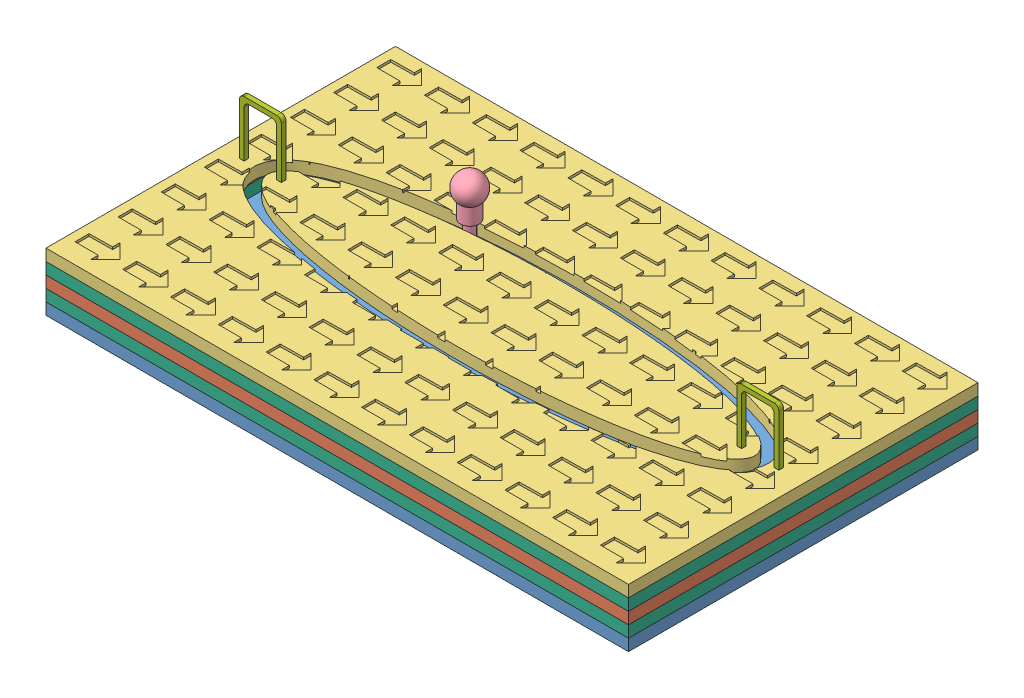
SolidWorks assembly Closedloopintegral, configuration Default. Lengths in mm.
Overall size (250 49 150).
9 component instances, 7 part files, 15 mates.
Components (placement in the parent):
- base1-1: base1 [Default] at (-49.7046 107.1468 237.7868) size (250 5 150)
- base2-2: base2 [Default] at (-49.7046 117.1468 237.7868) size (250 5 150)
- base3-1: base3 [Default] at (-49.7046 127.1468 237.7868) size (250 5 150)
- slider-1: slider [Default] at (32.305 122.1468 137.9363) x (0.152065 0 0.98837) z (-0.98837 0 0.152065) size (12.13 29.63 12.13)
- washer clip-1: washer clip [Default] at (32.305 122.1468 137.9363) x (-1 0 0) z (0 0 -1) size (11.02 5 8)
- base2_1-1: base2_1 [Default] at (-49.7046 112.1468 237.7868) size (250 5 150)
- base2_1-2: base2_1 [Default] at (-49.7046 122.1468 237.7868) size (250 5 150)
- holding mount-1: holding mount [Default] at (172.1186 132.1468 163.0837) size (18 24 2)
- holding mount-2: holding mount [Default] at (-41.546 132.1468 162.9308) size (18 24 2)
Mates (geometry in assembly coordinates):
- Coincident7: coincident aligned: circle of slider-1; circle of washer clip-1
- Coincident8: coincident anti-aligned: plane of base3-1 through (-49.7046 127.1468 237.7868) normal (0 -1 0); plane of washer clip-1 through (32.305 127.1468 137.9363) normal (0 1 0)
- Tangent3: tangent: face of base3-1; cylinder of slider-1 through (32.305 134.1468 137.9363) axis (0 -1 0) radius 2.2
- Coincident9: coincident anti-aligned: plane of base1-1 through (-49.7046 112.1468 237.7868) normal (0 1 0); plane of base2_1-1 through (-49.7046 112.1468 237.7868) normal (0 -1 0)
- Coincident10: coincident aligned: line of base1-1 through (-49.7046 112.1468 237.7868) axis (1 0 0); line of base2_1-1 through (-49.7046 112.1468 237.7868) axis (1 0 0)
- Coincident11: coincident aligned: line of base1-1 through (200.2954 112.1468 237.7868) axis (0 0 -1); line of base2_1-1 through (200.2954 112.1468 237.7868) axis (0 0 -1)
- Coincident12: coincident aligned: line of base2-2 through (200.2954 117.1468 237.7868) axis (0 0 -1); line of base2_1-1 through (200.2954 117.1468 237.7868) axis (0 0 -1)
- Coincident13: coincident aligned: line of base2-2 through (200.2954 117.1468 87.7868) axis (-1 0 0); line of base2_1-1 through (200.2954 117.1468 87.7868) axis (-1 0 0)
- Coincident14: coincident aligned: line of base2-2 through (200.2954 122.1468 237.7868) axis (0 0 -1); line of base2_1-2 through (200.2954 122.1468 237.7868) axis (0 0 -1)
- Coincident15: coincident aligned: line of base2-2 through (200.2954 122.1468 87.7868) axis (-1 0 0); line of base2_1-2 through (200.2954 122.1468 87.7868) axis (-1 0 0)
- Coincident16: coincident aligned: line of base3-1 through (200.2954 127.1468 237.7868) axis (0 0 -1); line of base2_1-2 through (200.2954 127.1468 237.7868) axis (0 0 -1)
- Coincident17: coincident aligned: line of base3-1 through (200.2954 127.1468 87.7868) axis (-1 0 0); line of base2_1-2 through (200.2954 127.1468 87.7868) axis (-1 0 0)
- Coincident18: coincident anti-aligned: plane of base3-1 through (-49.7046 132.1468 237.7868) normal (0 1 0); plane of holding mount-1 through (172.1186 132.1468 163.0837) normal (0 -1 0)
- Lock2: lock: unknown of base3-1; unknown of holding mount-2
- Parallel1: parallel anti-aligned: plane of base2-2 through (185.2954 117.1468 156.3095) normal (-1 0 0); plane of washer clip-1 through (39.3229 122.1468 136.4837) normal (1 0 0)
